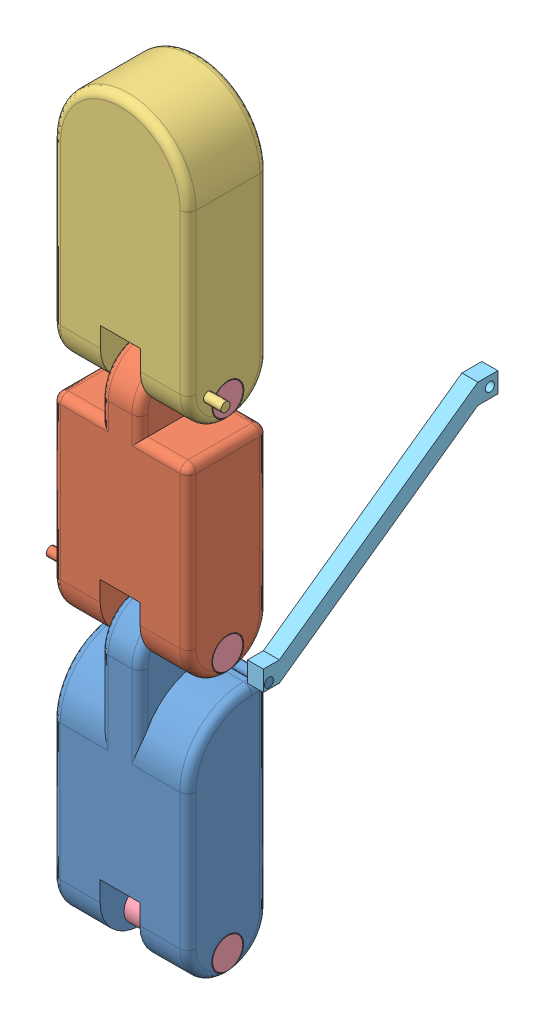
SolidWorks assembly Assem2, configuration Default. Lengths in mm.
Overall size (1279.38 851.97 642.84).
7 component instances, 5 part files, 12 mates.
Components (placement in the parent):
- bottomRing2-1: bottomRing2 [Default] at (65.8982 179.7909 355.869) size (192.89 374 100.1)
- upRing2-1: upRing2 [Default] at (66.0982 480.7909 355.869) size (193.09 324 100.1)
- topRing2-1: topRing2 [Default] at (66.2982 756.7909 355.869) size (193.09 335 100.1)
- WhitepinRing-1: WhitepinRing [Default] at (-18.9018 656.7909 305.869) x (0 0 -1) z (1 0 0) size (40 40 170)
- WhitepinRing-2: WhitepinRing [Default] at (-19.1018 380.7909 305.869) x (0 0 -1) z (1 0 0) size (40 40 170)
- WhitepinRing-3: WhitepinRing [Default] at (-19.1018 54.7909 305.869) x (0 0 -1) z (1 0 0) size (40 40 170)
- linkRing2-1: linkRing2 [Default] at (152.6982 527.269 -1.0982) x (0 -1 0) z (0 0 1) size (202.48 20 293.97)
Mates (geometry in assembly coordinates):
- Concentric1: concentric: cylinder of assembly; cylinder of assembly; cylinder of bottomRing2-1 through (150.8982 54.7909 305.869) axis (-1 0 0) radius 20; cylinder of WhitepinRing-3 through (150.8982 54.7909 305.869) axis (-1 0 0) radius 20
- Coincident1: coincident: plane of assembly; plane of assembly; plane of bottomRing2-1 through (-19.1018 329.7909 255.869) normal (-1 0 0); plane of WhitepinRing-3 through (-19.1018 54.7909 305.869) normal (-1 0 0)
- Concentric2: concentric: cylinder of assembly; cylinder of assembly; cylinder of bottomRing2-1 through (-19.1018 380.7909 305.869) axis (1 0 0) radius 20; cylinder of WhitepinRing-2 through (150.8982 380.7909 305.869) axis (-1 0 0) radius 20
- Coincident2: coincident: plane of assembly; plane of assembly; plane of bottomRing2-1 through (-19.1018 329.7909 255.869) normal (-1 0 0); plane of WhitepinRing-2 through (-19.1018 380.7909 305.869) normal (-1 0 0)
- Concentric3: concentric: cylinder of assembly; cylinder of assembly; cylinder of upRing2-1 through (151.0982 380.7909 305.869) axis (-1 0 0) radius 20; cylinder of WhitepinRing-2 through (150.8982 380.7909 305.869) axis (-1 0 0) radius 20
- Coincident3: coincident: plane of assembly; plane of assembly; plane of bottomRing2-1 through (41.0982 329.7909 255.869) normal (-1 0 0); plane of upRing2-1 through (41.0982 330.7909 255.869) normal (1 0 0)
- Concentric4: concentric: cylinder of assembly; cylinder of assembly; cylinder of upRing2-1 through (-19.9882 656.7909 305.869) axis (1 0 0) radius 20; cylinder of WhitepinRing-1 through (151.0982 656.7909 305.869) axis (-1 0 0) radius 20
- Coincident4: coincident: plane of assembly; plane of assembly; plane of upRing2-1 through (-18.9018 605.7909 255.869) normal (-1 0 0); plane of WhitepinRing-1 through (-18.9018 656.7909 305.869) normal (-1 0 0)
- Concentric5: concentric: cylinder of assembly; cylinder of assembly; cylinder of topRing2-1 through (151.2982 656.7909 305.869) axis (-1 0 0) radius 20; cylinder of WhitepinRing-1 through (151.0982 656.7909 305.869) axis (-1 0 0) radius 20
- Coincident5: coincident: plane of assembly; plane of assembly; plane of upRing2-1 through (41.2982 605.7909 255.869) normal (-1 0 0); plane of topRing2-1 through (41.2982 606.7909 255.869) normal (1 0 0)
- Concentric6: concentric: cylinder of assembly; cylinder of assembly; cylinder of bottomRing2-1 through (172.6982 344.7909 275.869) axis (-1 0 0) radius 5.75; cylinder of linkRing2-1 through (152.6982 344.7909 275.869) axis (1 0 0) radius 5.75
- Coincident6: coincident: plane of assembly; plane of assembly; plane of bottomRing2-1 through (172.6982 344.7909 275.869) normal (1 0 0); plane of linkRing2-1 through (172.6982 527.269 -1.0982) normal (1 0 0)
